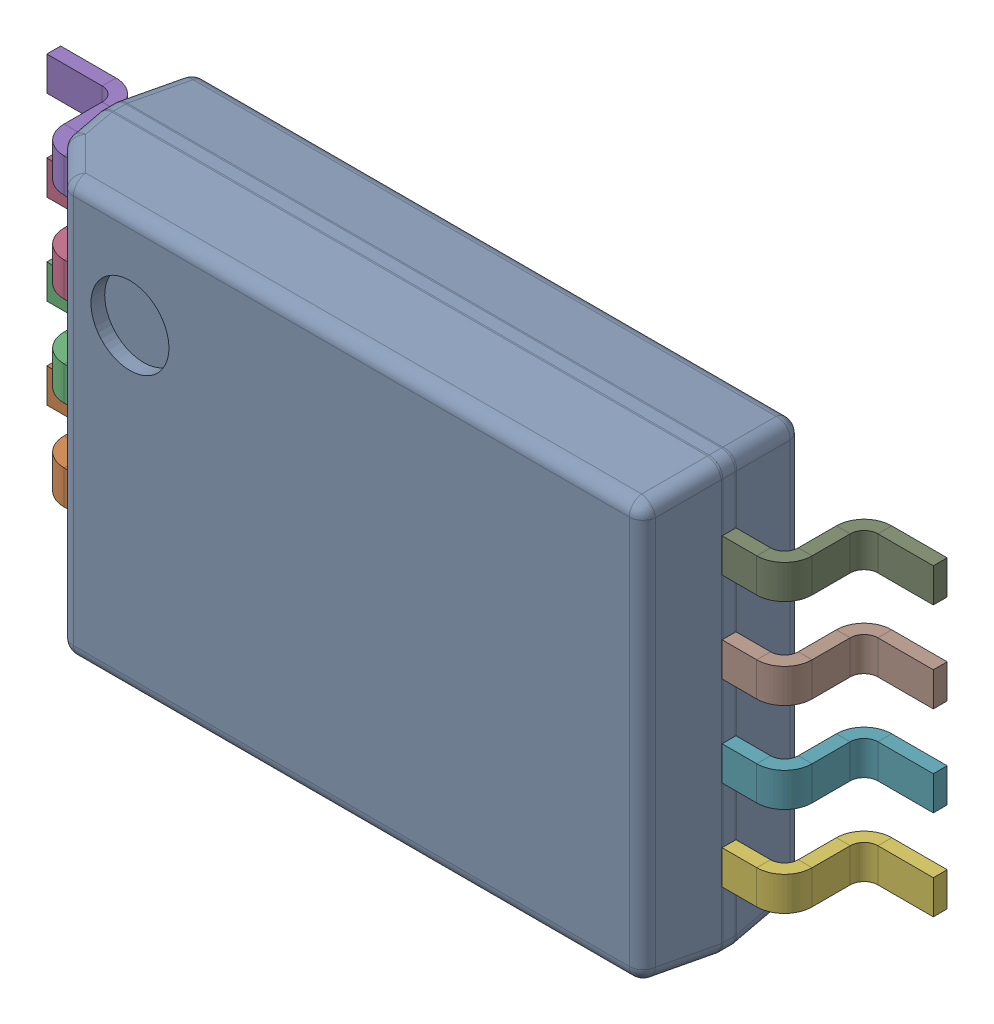
SolidWorks assembly 6297729728.step, configuration Default. Lengths in mm.
Overall size (6.4 4.19 1.2).
11 component instances, 3 part files, 0 mates.
Components (placement in the parent):
- Body (11).step-1: Body (11).step [Default] at (-2.25 -1.55 0) size (4.5 3.1 1.15)
  - Open CASCADE STEP translator 6.8 2.2.1 (3).step-1: Open CASCADE STEP translator 6.8 2.2.1 (3).step [Default] at origin size (4.5 3.1 1.15)
- Open CASCADE STEP translator 6.8 2.1 (3).step-1: Open CASCADE STEP translator 6.8 2.1 (3).step [Default] at (-2.25 -1.55 0.001) size (0.57 0.57 0.01)
- Leader.step-1: Leader.step [Default] at (-2.25 -0.975 0) x (-1 0 0) z (0 0 1) size (0.95 0.24 0.68)
- Leader.step-2: Leader.step [Default] at (-2.25 -0.325 0) x (-1 0 0) z (0 0 1) size (0.95 0.24 0.68)
- Leader.step-3: Leader.step [Default] at (-2.25 0.325 0) x (-1 0 0) z (0 0 1) size (0.95 0.24 0.68)
- Leader.step-4: Leader.step [Default] at (-2.25 0.975 0) x (-1 0 0) z (0 0 1) size (0.95 0.24 0.68)
- Leader.step-5: Leader.step [Default] at (2.25 -0.975 0) size (0.95 0.24 0.68)
- Leader.step-6: Leader.step [Default] at (2.25 -0.325 0) size (0.95 0.24 0.68)
- Leader.step-7: Leader.step [Default] at (2.25 0.325 0) size (0.95 0.24 0.68)
- Leader.step-8: Leader.step [Default] at (2.25 0.975 0) size (0.95 0.24 0.68)
